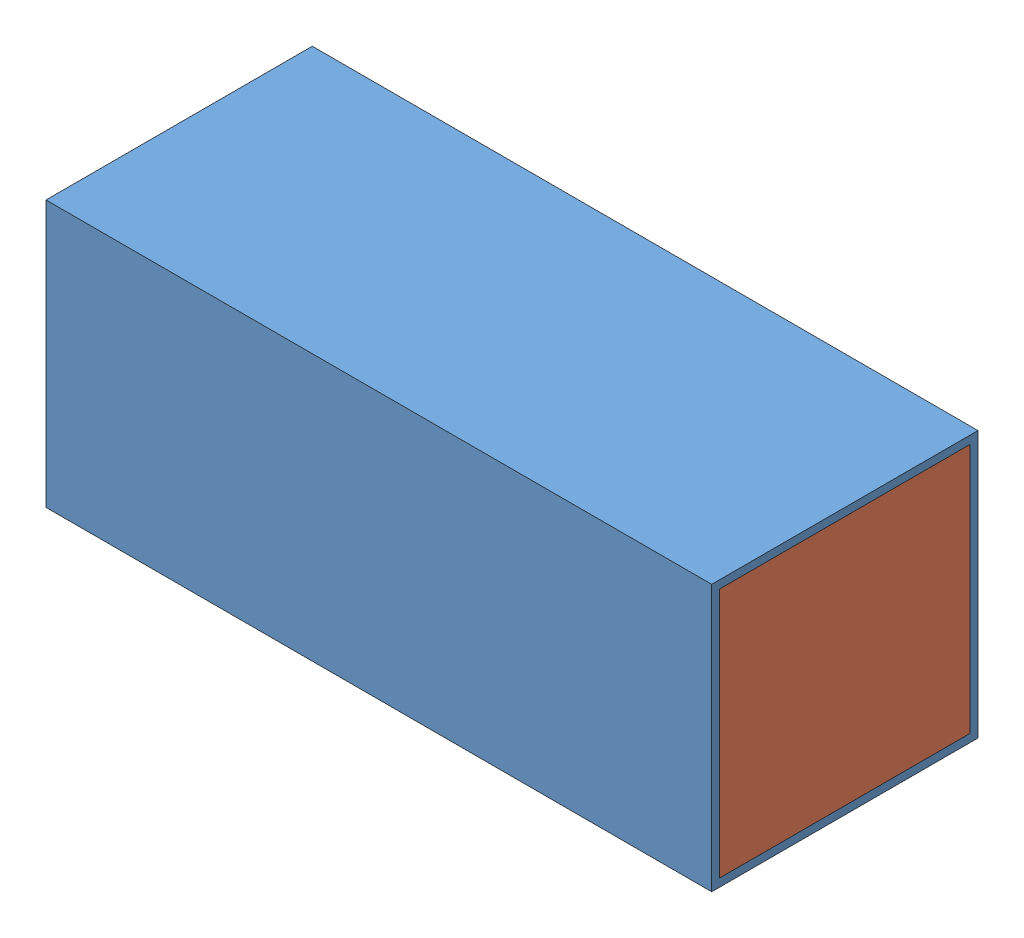
SolidWorks assembly Tunel de aire, configuration Predeterminado. Lengths in mm.
Overall size (250 100 100).
3 component instances, 3 part files, 0 mates.
Components (placement in the parent):
- Tunel-1: Tunel [Predeterminado] at (-150.8092 -50.9776 250) size (250 100 100)
- LID1-1: LID1 [Predeterminado] at origin size (1.44 96.66 96.66)
- LID2-1: LID2 [Predeterminado] at origin size (1.44 96.66 96.66)
